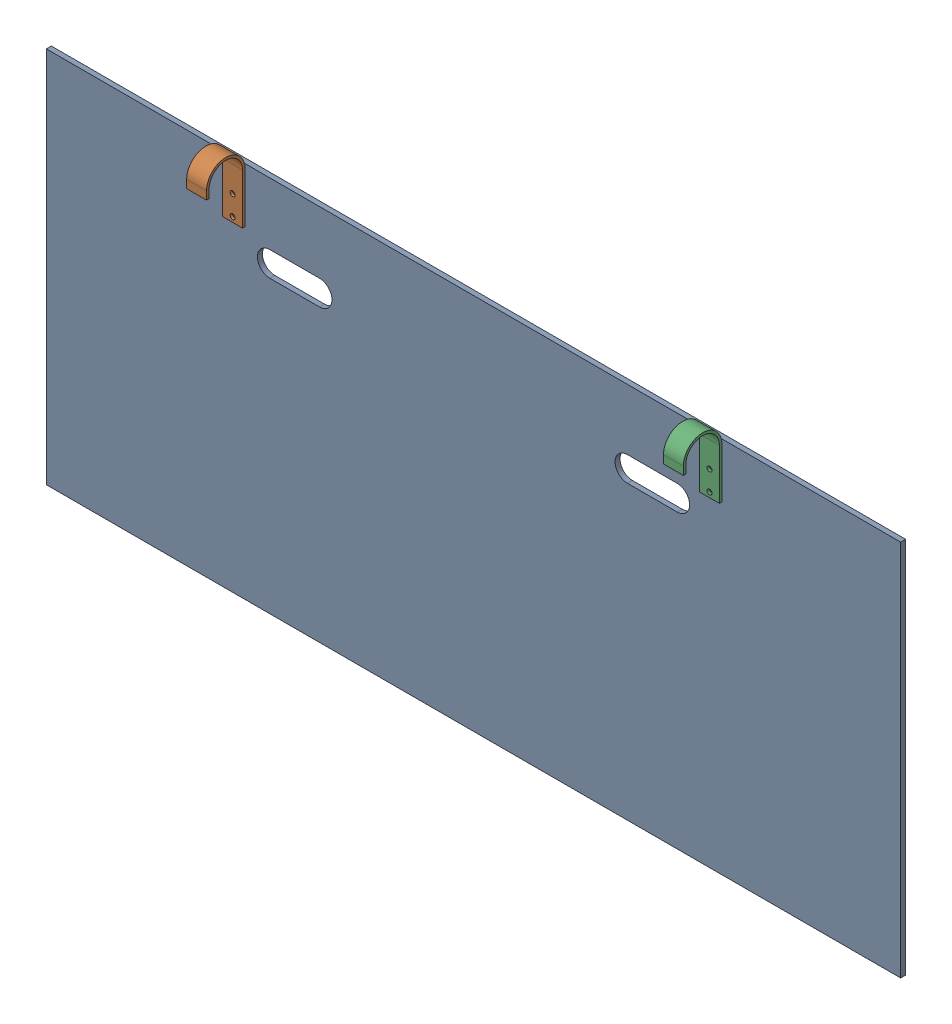
SolidWorks assembly FE-00017_, configuration Default. Lengths in mm.
Overall size (1092.2 501.65 55.56).
3 component instances, 2 part files, 0 mates.
Components (placement in the parent):
- FE-00011_-1: FE-00011_ [Default] at origin size (1092.2 482.6 6.35)
- FE-00016_-1: FE-00016_ [Default] at (123.4483 446.4825 49.2125) x (0 0 1) z (-1 0 0) size (49.21 88.9 25.4)
- FE-00016_-2: FE-00016_ [Default] at (733.0483 446.4825 49.2125) x (0 0 1) z (-1 0 0) size (49.21 88.9 25.4)
